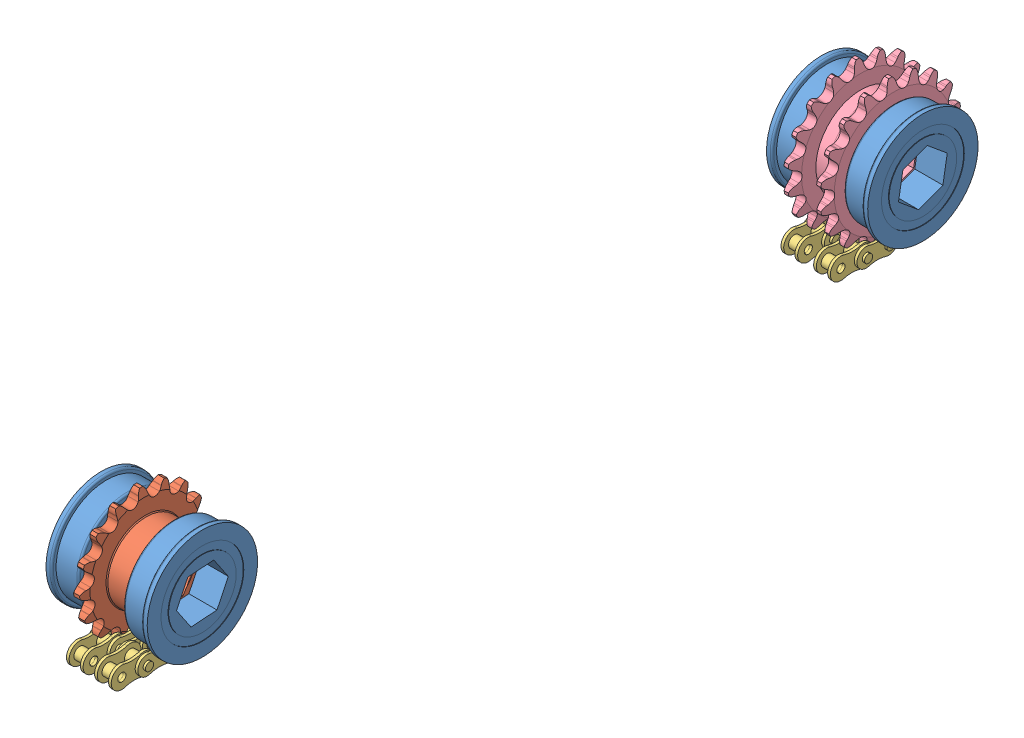
SolidWorks assembly Assem12, configuration Default. Lengths in mm.
Overall size (28.55 55.79 251.39).
12 component instances, 5 part files, 28 mates.
Components (placement in the parent):
- 2x1_Tube-1: 2x1_Tube [Default] at origin size (25.4 50.8 457.2) (hidden)
- 1.125Inch_Flange_Bearing-1: 1.125Inch_Flange_Bearing [Default] at (26.9748 25.4 406.4) x (0 1 0) z (0 0 1) size (31.12 7.92 31.12)
- 1.125Inch_Flange_Bearing-2: 1.125Inch_Flange_Bearing [Default] at (-1.5748 25.4 406.4) x (0 0.381849 -0.924225) z (0 -0.924225 -0.381849) size (31.12 7.92 31.12)
- am-0277_16Tooth_Sprocket-1: am-0277_16Tooth_Sprocket [Default] at (7.9375 25.4 406.4) x (0 -0.985891 0.167387) z (-1 0 0) size (35.21 35.21 10.86)
- 6261K281 ROLLER_CHAIN-1: 6261K281 ROLLER_CHAIN [6261K281] at (9.398 9.0868 418.6454) x (0 0.028167 -0.999603) z (1 0 0) size (31.03 5.99 7.62)
- 6261K281 ROLLER_CHAIN-2: 6261K281 ROLLER_CHAIN [6261K281] at (17.3263 9.0868 418.6454) x (0 0.028167 -0.999603) z (-1 0 0) size (31.03 5.99 7.62)
- 18Tooth_No25_Sprocket-1: 18Tooth_No25_Sprocket [Default] at (9.4932 25.4 203.2) x (0 -0.769236 0.638965) z (-1 0 0) size (39.82 39.37 6)
- 6261K281 ROLLER_CHAIN-3: 6261K281 ROLLER_CHAIN [6261K281] at (8.0962 7.4237 215.8158) x (0 -0.008373 -0.999965) z (-1 0 0) size (31.03 5.99 7.62)
- 1.125Inch_Flange_Bearing-3: 1.125Inch_Flange_Bearing [Default] at (26.9748 25.4 203.2) x (0 0.960543 0.278133) z (0 -0.278133 0.960543) size (31.12 7.92 31.12)
- 1.125Inch_Flange_Bearing-4: 1.125Inch_Flange_Bearing [Default] at (-1.5748 25.4 203.2) x (0 -0.097203 -0.995265) z (0 -0.995265 0.097203) size (31.12 7.92 31.12)
- 18Tooth_No25_Sprocket-2: 18Tooth_No25_Sprocket [Default] at (15.9068 25.4 203.2) x (0 -0.769236 0.638965) z (1 0 0) size (39.82 39.37 6)
- 6261K281 ROLLER_CHAIN-4: 6261K281 ROLLER_CHAIN [6261K281] at (17.3038 7.4237 215.8158) x (0 -0.008373 -0.999965) z (-1 0 0) size (31.03 5.99 7.62)
Mates (geometry in assembly coordinates):
- Concentric1: concentric aligned: circle of 2x1_Tube-1; cylinder of 1.125Inch_Flange_Bearing-1 through (19.05 25.4 406.4) axis (1 0 0) radius 14.2875
- Coincident1: coincident anti-aligned: plane of 2x1_Tube-1 through (25.4 0 457.2) normal (1 0 0); plane of 1.125Inch_Flange_Bearing-1 through (25.4 25.4 406.4) normal (-1 0 0)
- Coincident2: coincident anti-aligned: circle of 2x1_Tube-1; cylinder of 1.125Inch_Flange_Bearing-2 through (6.35 25.4 406.4) axis (-1 0 0) radius 14.2875
- Coincident3: coincident anti-aligned: plane of 2x1_Tube-1 through (0 0 457.2) normal (-1 0 0); plane of 1.125Inch_Flange_Bearing-2 through (0 25.4 406.4) normal (1 0 0)
- Concentric2: concentric anti-aligned: cylinder of 1.125Inch_Flange_Bearing-1 through (25.4 25.4 406.4) axis (1 0 0) radius 15.56; cylinder of am-0277_16Tooth_Sprocket-1 through (18.2245 25.4 406.4) axis (-1 0 0) radius 10.795
- Concentric3: concentric aligned: cylinder of am-0277_16Tooth_Sprocket-1 through (10.8585 9.534 402.7767) axis (-1 0 0) radius 1.6974; cylinder of 6261K281 ROLLER_CHAIN-1 through (10.9855 9.534 402.7767) axis (-1 0 0) radius 1.651
- Concentric4: concentric aligned: cylinder of am-0277_16Tooth_Sprocket-1 through (10.8585 9.3551 409.1241) axis (-1 0 0) radius 1.6974; cylinder of 6261K281 ROLLER_CHAIN-1 through (10.9855 9.3551 409.1241) axis (-1 0 0) radius 1.651
- Width1: width anti-aligned: plane of 6261K281 ROLLER_CHAIN-1 through (10.9855 14.9803 404.5183) normal (-1 0 0); plane of 6261K281 ROLLER_CHAIN-1 through (7.8105 14.9803 404.5183) normal (1 0 0); plane of am-0277_16Tooth_Sprocket-1 through (10.8585 25.4 406.4) normal (1 0 0); plane of am-0277_16Tooth_Sprocket-1 through (7.9375 25.4 406.4) normal (-1 0 0)
- Distance1: distance = 1.5875 mm anti-aligned: plane of am-0277_16Tooth_Sprocket-1 through (7.9375 25.4 406.4) normal (-1 0 0); plane of 1.125Inch_Flange_Bearing-2 through (6.35 25.4 406.4) normal (1 0 0)
- Concentric5: concentric anti-aligned: circle of 6261K281 ROLLER_CHAIN-1; circle of 6261K281 ROLLER_CHAIN-2
- Concentric6: concentric anti-aligned: circle of 6261K281 ROLLER_CHAIN-1; circle of 6261K281 ROLLER_CHAIN-2
- Concentric7: concentric anti-aligned: circle of 2x1_Tube-1; cylinder of 18Tooth_No25_Sprocket-1 through (15.875 25.4 203.2) axis (-1 0 0) radius 12.7
- Concentric8: concentric aligned: cylinder of 18Tooth_No25_Sprocket-1 through (6.6993 7.3439 206.2911) axis (1 0 0) radius 1.7367; cylinder of 6261K281 ROLLER_CHAIN-3 through (6.5088 7.3439 206.2911) axis (1 0 0) radius 1.651
- Width2: width anti-aligned: plane of 6261K281 ROLLER_CHAIN-3 through (9.6837 1.811 201.5748) normal (-1 0 0); plane of 6261K281 ROLLER_CHAIN-3 through (6.5088 1.811 201.5748) normal (1 0 0); plane of 18Tooth_No25_Sprocket-1 through (9.4932 25.4 203.2) normal (1 0 0); plane of 18Tooth_No25_Sprocket-1 through (6.6993 25.4 203.2) normal (-1 0 0)
- Tangent1: tangent aligned: cylinder of 18Tooth_No25_Sprocket-1 through (6.6993 7.3756 199.9292) axis (1 0 0) radius 1.7367; cylinder of 6261K281 ROLLER_CHAIN-3 through (6.5088 7.2907 199.9414) axis (1 0 0) radius 1.651
- Coincident4: coincident aligned: circle of 2x1_Tube-1; cylinder of 1.125Inch_Flange_Bearing-3 through (19.05 25.4 203.2) axis (1 0 0) radius 14.2875
- Coincident5: coincident anti-aligned: plane of 2x1_Tube-1 through (25.4 0 457.2) normal (1 0 0); plane of 1.125Inch_Flange_Bearing-3 through (25.4 25.4 203.2) normal (-1 0 0)
- Coincident6: coincident anti-aligned: plane of 2x1_Tube-1 through (0 0 457.2) normal (-1 0 0); plane of 1.125Inch_Flange_Bearing-4 through (0 25.4 203.2) normal (1 0 0)
- Coincident7: coincident anti-aligned: circle of 2x1_Tube-1; cylinder of 1.125Inch_Flange_Bearing-4 through (6.35 25.4 203.2) axis (-1 0 0) radius 14.2875
- Parallel4: parallel anti-aligned: line of 18Tooth_No25_Sprocket-1 through (6.6993 32.6417 201.9603) axis (0 -0.346696 0.937978); line of 1.125Inch_Flange_Bearing-3 through (19.05 30.0851 208.8403) axis (0 0.346696 -0.937978)
- Parallel5: parallel aligned: line of 18Tooth_No25_Sprocket-1 through (6.6993 32.6417 201.9603) axis (0 -0.346696 0.937978); line of 1.125Inch_Flange_Bearing-4 through (-1.5748 32.6272 201.9627) axis (0 -0.346696 0.937978)
- Coincident9: coincident anti-aligned: plane of 18Tooth_No25_Sprocket-1 through (12.7 25.4 203.2) normal (1 0 0); plane of 18Tooth_No25_Sprocket-2 through (12.7 25.4 203.2) normal (-1 0 0)
- Concentric13: concentric anti-aligned: cylinder of 18Tooth_No25_Sprocket-1 through (15.875 25.4 203.2) axis (-1 0 0) radius 12.7; cylinder of 18Tooth_No25_Sprocket-2 through (9.525 25.4 203.2) axis (1 0 0) radius 12.7
- Parallel6: parallel aligned: line of 18Tooth_No25_Sprocket-1 through (6.6993 27.9472 196.3087) axis (0 0.638965 0.769236); line of 18Tooth_No25_Sprocket-2 through (12.7 27.9472 196.3087) axis (0 0.638965 0.769236)
- Width4: width anti-aligned: plane of 6261K281 ROLLER_CHAIN-4 through (15.7163 1.811 201.5748) normal (1 0 0); plane of 6261K281 ROLLER_CHAIN-4 through (18.8912 1.811 201.5748) normal (-1 0 0); plane of 18Tooth_No25_Sprocket-2 through (15.9068 25.4 203.2) normal (-1 0 0); plane of 18Tooth_No25_Sprocket-2 through (18.7007 25.4 203.2) normal (1 0 0)
- Concentric14: concentric anti-aligned: cylinder of 18Tooth_No25_Sprocket-2 through (18.7007 7.3439 206.2911) axis (-1 0 0) radius 1.7367; cylinder of 6261K281 ROLLER_CHAIN-4 through (15.7163 7.3439 206.2911) axis (1 0 0) radius 1.651
- Tangent2: tangent aligned: cylinder of 18Tooth_No25_Sprocket-2 through (18.7007 7.3756 199.9292) axis (-1 0 0) radius 1.7367; cylinder of 6261K281 ROLLER_CHAIN-4 through (15.7163 7.2907 199.9414) axis (1 0 0) radius 1.651
- Width5: width anti-aligned: plane of 18Tooth_No25_Sprocket-1 through (6.6993 25.4 203.2) normal (-1 0 0); plane of 18Tooth_No25_Sprocket-2 through (18.7007 25.4 203.2) normal (1 0 0); plane of 1.125Inch_Flange_Bearing-4 through (6.35 25.4 203.2) normal (1 0 0); plane of 1.125Inch_Flange_Bearing-3 through (19.05 25.4 203.2) normal (-1 0 0)
